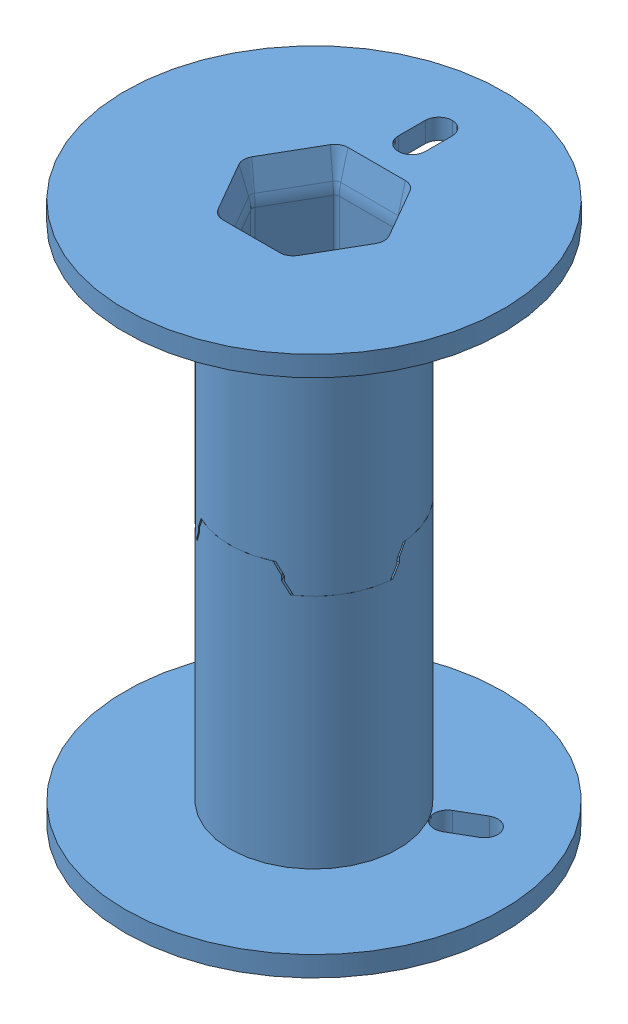
SolidWorks assembly electromagnet, configuration Default. Lengths in mm.
Overall size (30.36 31.75 30.36).
5 component instances, 4 part files, 12 mates.
Components (placement in the parent):
- custom_spool-1: custom_spool [Xometry - Light Clearance] at origin size (22.23 16.67 22.23)
- custom_spool-2: custom_spool [Xometry - Light Clearance] x (-0.5 0 -0.866025) z (-0.866025 0 0.5) size (22.23 16.67 22.23)
- 91920A201_Female Threaded Hex Standoff-1: 91920A201_Female Threaded Hex Standoff [91920A201] x (-0.866025 0 -0.5) z (0 -1 0) size (6.35 7.33 32.35) (hidden)
- 91375A773_Alloy Steel Cup-Point Set Screw-1: 91375A773_Alloy Steel Cup-Point Set Screw [91375A773] at (0 11.1125 0) x (0 0 1) z (0 1 0) size (4.34 4.28 9.88) (hidden)
- Part4^electromagnet-1: Part4^electromagnet [Default] at origin size (20.64 29.37 20.64) (hidden, virtual)
Mates (geometry in assembly coordinates):
- Coincident2: coincident anti-aligned: plane of custom_spool-1 through (0 -0.7937 0) normal (0 1 0); plane of custom_spool-2 through (0 -0.7937 0) normal (0 -1 0)
- Angle1: planar angle = 0 rad anti-aligned: plane of custom_spool-1 through (-0.055 -0.7937 0.0318) normal (0.866025 0 -0.5); plane of custom_spool-2 through (0.055 0.7937 -0.0318) normal (-0.866025 0 0.5)
- Coincident6: coincident aligned: plane of custom_spool-1 through (0 -15.875 0) normal (0 -1 0); plane of 91920A201_Female Threaded Hex Standoff-1 through (1.8331 -15.875 -3.175) normal (0 -1 0)
- Concentric2: concentric aligned: cylinder of custom_spool-2 through (0 -15.875 0) axis (0 1 0) radius 4.953; circle of 91920A201_Female Threaded Hex Standoff-1
- Parallel1: parallel anti-aligned: plane of custom_spool-1 through (-1.8331 15.875 3.175) normal (0 0 -1); plane of 91920A201_Female Threaded Hex Standoff-1 through (1.8331 -15.875 3.175) normal (0 0 1)
- Concentric3: concentric anti-aligned: cylinder of custom_spool-1 through (0 15.875 0) axis (0 -1 0) radius 4.953; cylinder of custom_spool-2 through (0 -15.875 0) axis (0 1 0) radius 4.953
- Coincident7: coincident anti-aligned: plane of 91920A201_Female Threaded Hex Standoff-1 through (1.8331 15.875 -3.175) normal (0 1 0); circle of 91375A773_Alloy Steel Cup-Point Set Screw-1
- Concentric4: concentric anti-aligned: line of 91920A201_Female Threaded Hex Standoff-1; line of 91375A773_Alloy Steel Cup-Point Set Screw-1 through (0 9.3324 0) axis (0 1 0)
- Parallel2: parallel anti-aligned: plane of 91920A201_Female Threaded Hex Standoff-1 through (-1.8331 -15.875 -3.175) normal (0 0 -1); plane of 91375A773_Alloy Steel Cup-Point Set Screw-1 through (0 11.1125 0) normal (0 0 1)
- Coincident11: coincident aligned: plane of custom_spool-1 through (0 0 0) normal (1 0 0)
- Coincident12: coincident aligned: plane of custom_spool-1 through (0 0 0) normal (0 0 1)
- Coincident13: coincident aligned: plane of custom_spool-1 through (0 0 0) normal (0 1 0)
